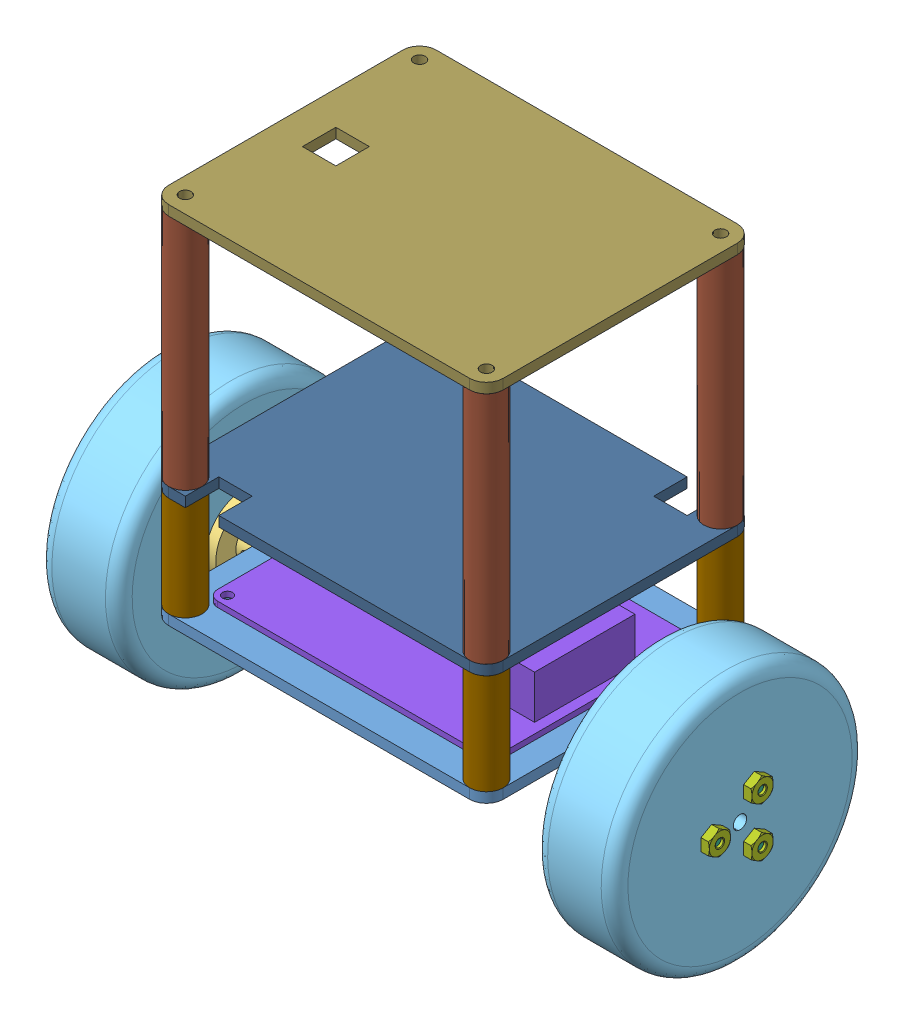
SolidWorks assembly main, configuration Default. Lengths in mm.
Overall size (177.86 165.23 103.14).
34 component instances, 12 part files, 35 mates.
Components (placement in the parent):
- 05_plate_0-1: 05_plate_0 [Default] at (56.2824 96.5369 150.2079) size (100 3 80)
- motor_assembly-1: motor_assembly [Default] at (76.944 129.3735 158.3262) x (0 0 -1) z (0 -1 0) size (102.45 66.46 102.45)
  - 01_micro_metal_gearmotor-1: 01_micro_metal_gearmotor [По умолчанию] at (7.6392 6.8545 37.8366) size (12.1 35.27 10.12)
  - 02_motor_hub-1: 02_motor_hub [Default] at (7.6392 33.6245 37.8366) x (0 0 -1) z (1 0 0) size (23 8 23)
  - 03_motor_mount-1: 03_motor_mount [Default] at (-5.1608 -3.6518 104.3827) x (0 0.08713 -0.996197) z (1 0 0) size (12.96 18.24 26.57)
  - 04_wheel-1: 04_wheel [Default] at (7.6392 41.6245 37.8366) x (0.866025 0 -0.5) z (0 1 0) size (75 75 24)
  - pan cross head_ai-1: pan cross head_ai [CR-PHMS 0.112-40x1.125x1.125-N] at (-0.8608 36.5925 37.8366) x (0 1 0) z (0 0 1) size (30.57 5.56 5.56)
  - pan cross head_ai-2: pan cross head_ai [CR-PHMS 0.112-40x1.125x1.125-N] at (11.8892 36.5925 30.4754) x (0 1 0) z (-0.866025 0 -0.5) size (30.57 5.56 5.56)
  - pan cross head_ai-3: pan cross head_ai [CR-PHMS 0.112-40x1.125x1.125-N] at (11.8892 36.5925 45.1978) x (0 1 0) z (0.866025 0 -0.5) size (30.57 5.56 5.56)
  - machine screw nut hex_ai-1: machine screw nut hex_ai [MSHXNUT 0.112-48-S-N] at (-0.8608 68.1137 37.8366) x (1 0 0) z (0 1 0) size (6.35 7.33 2.49)
  - machine screw nut hex_ai-2: machine screw nut hex_ai [MSHXNUT 0.112-48-S-N] at (11.8892 68.1137 45.1978) x (-0.5 0 -0.866025) z (0 1 0) size (6.35 7.33 2.49)
  - machine screw nut hex_ai-3: machine screw nut hex_ai [MSHXNUT 0.112-48-S-N] at (11.8892 68.1137 30.4754) x (-0.5 0 0.866025) z (0 1 0) size (6.35 7.33 2.49)
- motor_assembly-2: motor_assembly [Default] at (35.3158 129.3735 142.3644) x (0 0 1) z (0 -1 0) size (102.45 66.46 102.45)
  - 01_micro_metal_gearmotor-1: 01_micro_metal_gearmotor [По умолчанию] at (7.6392 6.8545 37.8366) size (12.1 35.27 10.12)
  - 02_motor_hub-1: 02_motor_hub [Default] at (7.6392 33.6245 37.8366) x (0 0 -1) z (1 0 0) size (23 8 23)
  - 03_motor_mount-1: 03_motor_mount [Default] at (-5.1608 -3.6518 104.3827) x (0 0.08713 -0.996197) z (1 0 0) size (12.96 18.24 26.57)
  - 04_wheel-1: 04_wheel [Default] at (7.6392 41.6245 37.8366) x (0.866025 0 -0.5) z (0 1 0) size (75 75 24)
  - pan cross head_ai-1: pan cross head_ai [CR-PHMS 0.112-40x1.125x1.125-N] at (-0.8608 36.5925 37.8366) x (0 1 0) z (0 0 1) size (30.57 5.56 5.56)
  - pan cross head_ai-2: pan cross head_ai [CR-PHMS 0.112-40x1.125x1.125-N] at (11.8892 36.5925 30.4754) x (0 1 0) z (-0.866025 0 -0.5) size (30.57 5.56 5.56)
  - pan cross head_ai-3: pan cross head_ai [CR-PHMS 0.112-40x1.125x1.125-N] at (11.8892 36.5925 45.1978) x (0 1 0) z (0.866025 0 -0.5) size (30.57 5.56 5.56)
  - machine screw nut hex_ai-1: machine screw nut hex_ai [MSHXNUT 0.112-48-S-N] at (-0.8608 68.1137 37.8366) x (1 0 0) z (0 1 0) size (6.35 7.33 2.49)
  - machine screw nut hex_ai-2: machine screw nut hex_ai [MSHXNUT 0.112-48-S-N] at (11.8892 68.1137 45.1978) x (-0.5 0 -0.866025) z (0 1 0) size (6.35 7.33 2.49)
  - machine screw nut hex_ai-3: machine screw nut hex_ai [MSHXNUT 0.112-48-S-N] at (11.8892 68.1137 30.4754) x (-0.5 0 0.866025) z (0 1 0) size (6.35 7.33 2.49)
- 06_mdd10a-1: 06_mdd10a [Default] at (56.2824 99.5369 150.2079) size (84.8 14.65 62)
- 07_rod_3mm-1: 07_rod_3mm [Default] at (11.2824 99.5369 185.2079) x (0.868762 0 0.49523) z (-0.49523 0 0.868762) size (10 30 10)
- 07_rod_3mm-2: 07_rod_3mm [Default] at (101.2824 99.5369 115.2079) size (10 30 10)
- 07_rod_3mm-3: 07_rod_3mm [Default] at (101.2824 129.5369 185.2079) x (-0.727661 0 -0.685936) z (-0.685936 0 0.727661) size (10 30 10)
- 07_rod_3mm-4: 07_rod_3mm [Default] at (11.2824 129.5369 115.2079) x (-0.781501 0 -0.623904) z (-0.623904 0 0.781501) size (10 30 10)
- 05_plate_1-1: 05_plate_1 [Default] at (56.2824 129.5369 150.2079) size (100 3 80)
- 07_rod_7mm-1: 07_rod_7mm [Default] at (101.2824 132.5369 185.2079) x (0.782948 0 -0.622087) z (0.622087 0 0.782948) size (10 70 10)
- 07_rod_7mm-2: 07_rod_7mm [Default] at (11.2824 132.5369 115.2079) x (0.827033 0 0.562154) z (-0.562154 0 0.827033) size (10 70 10)
- 07_rod_7mm-3: 07_rod_7mm [Default] at (11.2824 132.5369 185.2079) x (0.963961 0 0.266044) z (-0.266044 0 0.963961) size (10 70 10)
- 07_rod_7mm-4: 07_rod_7mm [Default] at (101.2824 132.5369 115.2079) x (0.975849 0 -0.218448) z (0.218448 0 0.975849) size (10 70 10)
- 05_plate_2-1: 05_plate_2 [Default] at (56.2824 202.5369 150.2079) size (100 3 80)
Mates (geometry in assembly coordinates):
- Parallel5: parallel anti-aligned: plane of 05_plate_0-1 through (6.2824 99.5369 115.2079) normal (-1 0 0); plane of motor_assembly-1/01_micro_metal_gearmotor-1 through (106.2985 91.5369 150.687) normal (1 0 0)
- Coincident5: coincident anti-aligned: plane of 05_plate_0-1 through (101.2824 96.5369 115.2079) normal (0 -1 0); plane of motor_assembly-1/01_micro_metal_gearmotor-1 through (97.2985 96.5369 154.0036) normal (0 1 0)
- Parallel6: parallel aligned: plane of 05_plate_0-1 through (6.2824 99.5369 115.2079) normal (-1 0 0); plane of motor_assembly-2/01_micro_metal_gearmotor-1 through (5.9613 91.5369 150.0036) normal (-1 0 0)
- Coincident7: coincident anti-aligned: plane of 05_plate_0-1 through (101.2824 96.5369 115.2079) normal (0 -1 0); plane of motor_assembly-2/01_micro_metal_gearmotor-1 through (14.9613 96.5369 146.687) normal (0 1 0)
- Lock1: lock: unknown of 05_plate_0-1; unknown of motor_assembly-2/03_motor_mount-1
- Lock2: lock: unknown of 05_plate_0-1; unknown of motor_assembly-1/03_motor_mount-1
- Coincident10: coincident aligned: plane of 05_plate_0-1 through (101.2824 99.5369 115.2079) normal (0 1 0); circle of 07_rod_3mm-1
- Coincident11: coincident anti-aligned: plane of 05_plate_0-1 through (101.2824 99.5369 115.2079) normal (0 1 0); plane of 07_rod_3mm-2 through (101.2824 99.5369 115.2079) normal (0 -1 0)
- Coincident12: coincident anti-aligned: plane of 05_plate_0-1 through (101.2824 99.5369 115.2079) normal (0 1 0); circle of 07_rod_3mm-3
- Coincident13: coincident anti-aligned: plane of 05_plate_0-1 through (101.2824 99.5369 115.2079) normal (0 1 0); circle of 07_rod_3mm-4
- Concentric4: concentric anti-aligned: circle of 05_plate_0-1; circle of 07_rod_3mm-1
- Concentric5: concentric anti-aligned: circle of 05_plate_0-1; cylinder of 07_rod_3mm-3 through (101.2824 129.5369 185.2079) axis (0 -1 0) radius 2
- Concentric6: concentric anti-aligned: circle of 05_plate_0-1; circle of 07_rod_3mm-2
- Concentric7: concentric aligned: circle of 05_plate_0-1; circle of 07_rod_3mm-4
- Concentric9: concentric aligned: circle of 05_plate_0-1; circle of 06_mdd10a-1
- Concentric8: concentric aligned: circle of 05_plate_0-1; circle of 06_mdd10a-1
- Coincident16: coincident anti-aligned: plane of 05_plate_0-1 through (101.2824 99.5369 115.2079) normal (0 1 0); plane of 06_mdd10a-1 through (56.2824 99.5369 150.2079) normal (0 -1 0)
- Concentric10: concentric aligned: circle of 07_rod_3mm-3; circle of 05_plate_1-1
- Concentric11: concentric aligned: cylinder of 07_rod_3mm-1 through (11.2824 99.5369 185.2079) axis (0 1 0) radius 2; circle of 05_plate_1-1
- Concentric12: concentric aligned: circle of 07_rod_3mm-4; circle of 05_plate_1-1
- Concentric13: concentric anti-aligned: circle of 07_rod_3mm-2; circle of 05_plate_1-1
- Coincident17: coincident anti-aligned: circle of 07_rod_3mm-1; plane of 05_plate_1-1 through (101.2824 129.5369 115.2079) normal (0 -1 0)
- Concentric14: concentric anti-aligned: circle of 05_plate_1-1; circle of 07_rod_7mm-1
- Coincident18: coincident anti-aligned: plane of 05_plate_1-1 through (101.2824 132.5369 115.2079) normal (0 1 0); plane of 07_rod_7mm-1 through (101.2824 132.5369 185.2079) normal (0 -1 0)
- Concentric15: concentric aligned: circle of 05_plate_1-1; cylinder of 07_rod_7mm-3 through (11.2824 132.5369 185.2079) axis (0 1 0) radius 2
- Coincident19: coincident: plane of 05_plate_1-1 through (101.2824 132.5369 115.2079) normal (0 1 0); line of 07_rod_7mm-3 through (12.0939 132.5369 188.2778) axis (0.709484 0 -0.704722)
- Concentric16: concentric anti-aligned: circle of 05_plate_1-1; circle of 07_rod_7mm-2
- Coincident20: coincident anti-aligned: plane of 05_plate_1-1 through (101.2824 132.5369 115.2079) normal (0 1 0); plane of 07_rod_7mm-2 through (11.2824 132.5369 115.2079) normal (0 -1 0)
- Concentric17: concentric anti-aligned: circle of 05_plate_1-1; circle of 07_rod_7mm-4
- Coincident21: coincident anti-aligned: plane of 05_plate_1-1 through (101.2824 132.5369 115.2079) normal (0 1 0); plane of 07_rod_7mm-4 through (101.2824 132.5369 115.2079) normal (0 -1 0)
- Concentric18: concentric anti-aligned: circle of 07_rod_7mm-3; circle of 05_plate_2-1
- Concentric19: concentric anti-aligned: circle of 07_rod_7mm-1; circle of 05_plate_2-1
- Concentric20: concentric aligned: cylinder of 07_rod_7mm-4 through (101.2824 132.5369 115.2079) axis (0 1 0) radius 2; circle of 05_plate_2-1
- Concentric21: concentric anti-aligned: circle of 07_rod_7mm-2; circle of 05_plate_2-1
- Coincident22: coincident anti-aligned: circle of 07_rod_7mm-2; plane of 05_plate_2-1 through (101.2824 202.5369 115.2079) normal (0 -1 0)
